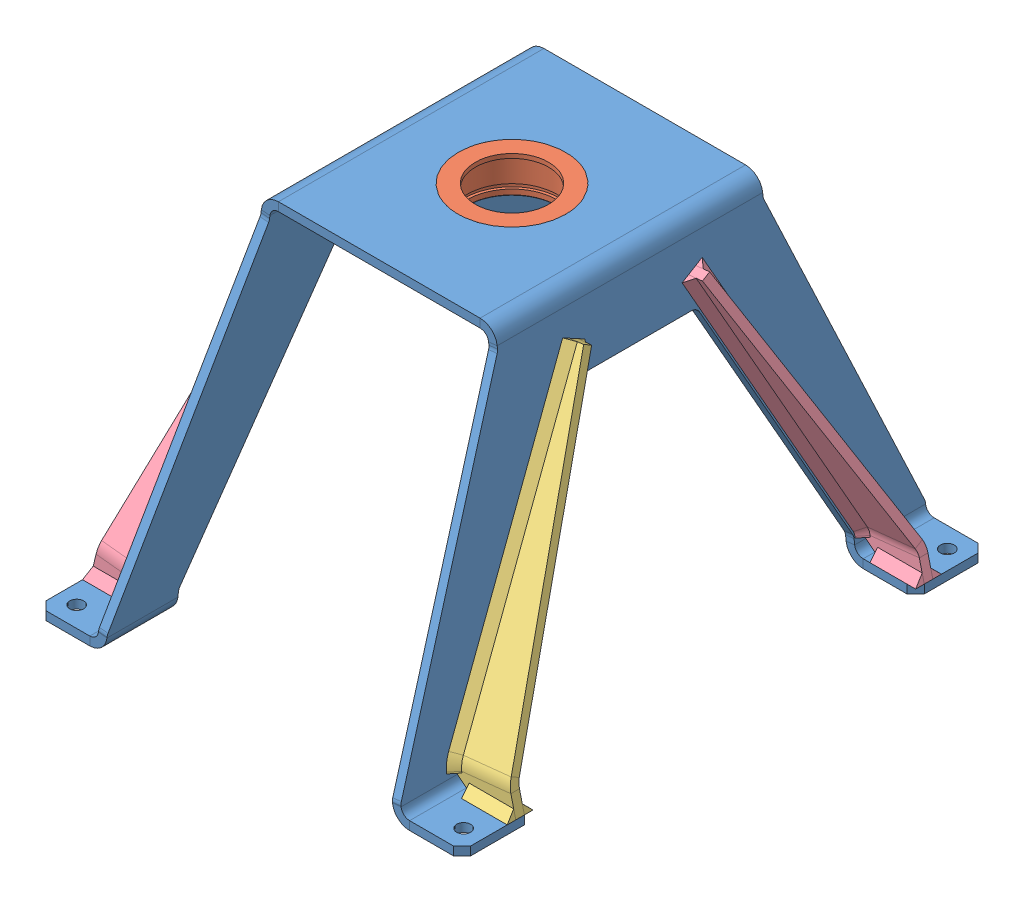
SolidWorks assembly Швеллер домкрата верхний со втулкой, configuration По умолчанию. Lengths in mm.
Overall size (197.54 162.58 244).
7 component instances, 5 part files, 15 mates.
Components (placement in the parent):
- Швеллер домкрата верхний в5-1: Швеллер домкрата верхний в5 [По умолчанию] at origin size (197.54 162.58 244)
- Стакан верхнего радиального подшипника-1: Стакан верхнего радиального подшипника [По умолчанию] at (0 29 0) x (-1 0 0) z (0 0 1) size (55 20 55)
- bead1-1: bead1 [По умолчанию] at origin
- Ребро кронштейна верхнего подшипника в2-1: Ребро кронштейна верхнего подшипника в2 [со сварными швами] at (70.7692 -129.5819 93) x (0.994522 0.104528 0) z (0 0 1) size (27.85 144.23 78.39)
- Ребро зеркало кронштейна верхнего подшипника в2-1: Ребро зеркало кронштейна верхнего подшипника в2 [со сварными швами] at (70.7692 -129.5819 -97) x (0.994522 0.104528 0) z (0 0 1) size (27.85 144.23 78.39)
- Ребро кронштейна верхнего подшипника в2-2: Ребро кронштейна верхнего подшипника в2 [со сварными швами] at (-70.7692 -129.5819 -93) x (-0.994522 0.104528 0) z (0 0 -1) size (27.85 144.23 78.39)
- Ребро зеркало кронштейна верхнего подшипника в2-2: Ребро зеркало кронштейна верхнего подшипника в2 [со сварными швами] at (-70.7692 -129.5819 97) x (-0.994522 0.104528 0) z (0 0 -1) size (27.85 144.23 78.39)
Mates (geometry in assembly coordinates):
- Совпадение1: coincident anti-aligned: plane of Стакан верхнего радиального подшипника-1 through (-27.5 25 0) normal (0 1 0); plane of ? through (-50.5 25 61.75) normal (0 -1 0)
- Концентрический1: concentric aligned: cylinder of ? through (0 25 0) axis (0 1 0) radius 25; cylinder of Стакан верхнего радиального подшипника-1 through (0 29 0) axis (0 1 0) radius 25
- Параллельность1: parallel aligned: plane of Стакан верхнего радиального подшипника-1 through (0 29 0) normal (0 0 1); plane of assembly through (0 0 0) normal (0 0 1)
- Совпадение5: coincident anti-aligned: plane of ? through (70.7692 -129.5819 89) normal (0 1 0); plane of Ребро кронштейна верхнего подшипника в2-1 through (70.7692 -129.5819 97) normal (0 -1 0)
- Расстояние2: distance = 4 mm aligned: plane of ? through (98.7692 -133.5819 89) normal (0 0 -1); plane of Ребро кронштейна верхнего подшипника в2-1 through (54.5673 24.569 93) normal (0 0 -1)
- Совпадение6: coincident anti-aligned: plane of ? through (57.1057 0.4181 61.75) normal (0.994522 0.104528 0); plane of Ребро кронштейна верхнего подшипника в2-1 through (56.1707 9.314 29.3015) normal (-0.994522 -0.104528 0)
- Совпадение7: coincident anti-aligned: plane of ? through (98.7692 -129.5819 -89) normal (0 1 0); plane of Ребро зеркало кронштейна верхнего подшипника в2-1 through (70.7692 -129.5819 -93) normal (0 -1 0)
- Совпадение8: coincident anti-aligned: plane of ? through (57.1057 0.4181 61.75) normal (0.994522 0.104528 0); plane of Ребро зеркало кронштейна верхнего подшипника в2-1 through (56.3638 7.4771 -25.7534) normal (-0.994522 -0.104528 0)
- Расстояние3: distance = 4 mm aligned: plane of Ребро зеркало кронштейна верхнего подшипника в2-1 through (54.5673 24.569 -93) normal (0 0 1); plane of ? through (70.7692 -133.5819 -89) normal (0 0 1)
- Совпадение10: coincident anti-aligned: plane of Ребро зеркало кронштейна верхнего подшипника в2-2 through (-56.3638 7.4771 25.7534) normal (0.994522 -0.104528 0); plane of ? through (-57.1057 0.4181 61.75) normal (-0.994522 0.104528 0)
- Совпадение11: coincident anti-aligned: plane of Ребро зеркало кронштейна верхнего подшипника в2-2 through (-70.7692 -129.5819 93) normal (0 -1 0); plane of ? through (-70.7692 -129.5819 122) normal (0 1 0)
- Расстояние4: distance = 4 mm aligned: plane of Ребро зеркало кронштейна верхнего подшипника в2-2 through (-54.5673 24.569 93) normal (0 0 -1); plane of ? through (-70.7692 -133.5819 89) normal (0 0 -1)
- Совпадение13: coincident anti-aligned: plane of ? through (-70.7692 -129.5819 -89) normal (0 1 0); plane of Ребро кронштейна верхнего подшипника в2-2 through (-70.7692 -129.5819 -97) normal (0 -1 0)
- Совпадение14: coincident anti-aligned: plane of ? through (-57.1057 0.4181 61.75) normal (-0.994522 0.104528 0); plane of Ребро кронштейна верхнего подшипника в2-2 through (-56.1707 9.314 -29.3015) normal (0.994522 -0.104528 0)
- Расстояние5: distance = 4 mm aligned: plane of ? through (-98.7692 -133.5819 -89) normal (0 0 1); plane of Ребро кронштейна верхнего подшипника в2-2 through (-54.5673 24.569 -93) normal (0 0 1)
